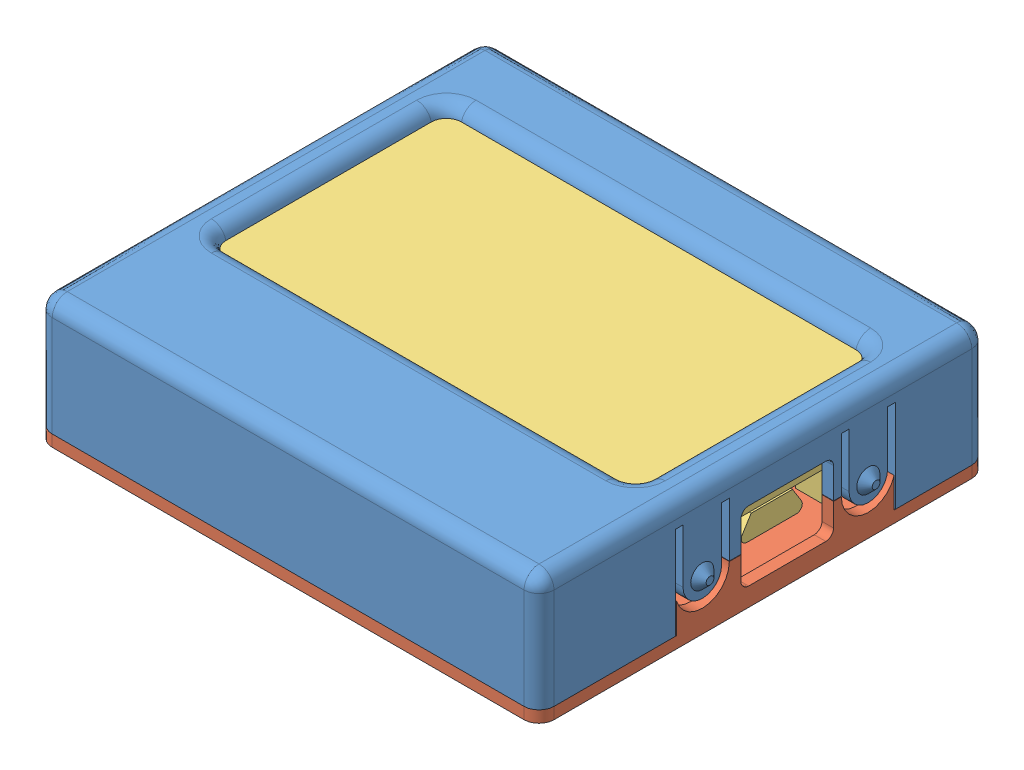
SolidWorks assembly PixlJsCase, configuration Default. Lengths in mm.
Overall size (67 16.5 58).
3 component instances, 3 part files, 4 mates.
Components (placement in the parent):
- TOP^PixlJsCase-1: TOP^PixlJsCase [Default] at (-27.2204 8.6792 -35.4841) size (67 15 58) (virtual)
- BOT^PixlJsCase-1: BOT^PixlJsCase [Default] at (-11.0692 -4.8208 -19.0067) size (65 9.15 58) (virtual)
- PixlJs-1: PixlJs [Default] at (-26.2981 3.5792 -19.2671) size (60.75 14.96 53.5)
Mates (geometry in assembly coordinates):
- Coincident11: coincident anti-aligned: plane of TOP^PixlJsCase-1 through (-27.2204 -3.3208 -35.4841) normal (0 -1 0); plane of BOT^PixlJsCase-1 through (-11.0692 -3.3208 -19.0067) normal (0 1 0)
- Coincident12: coincident aligned: plane of TOP^PixlJsCase-1 through (-59.7685 10.1792 -55.2314) normal (0 0 -1); plane of BOT^PixlJsCase-1 through (-59.7685 -3.3208 -55.2314) normal (0 0 -1)
- Coincident13: coincident aligned: plane of TOP^PixlJsCase-1 through (5.2315 10.1792 -55.2314) normal (1 0 0); plane of BOT^PixlJsCase-1 through (5.2315 -3.3208 -55.2314) normal (1 0 0)
- Concentric1: concentric anti-aligned: circle of TOP^PixlJsCase-1; circle of PixlJs-1
